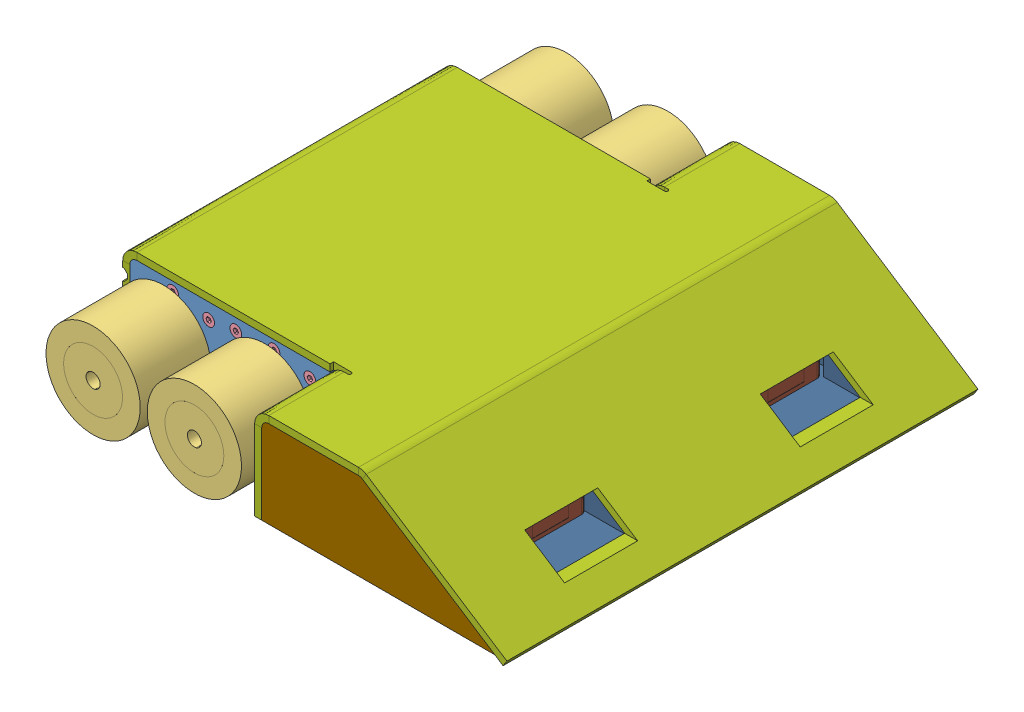
SolidWorks assembly Robot, configuration Predeterminado. Lengths in mm.
Overall size (195.19 45.36 282.25).
54 component instances, 11 part files, 14 mates.
Components (placement in the parent):
- Tren_Trasero-1: Tren_Trasero [Predeterminado] at (-15.877 7.2886 280.5) size (88.08 45.36 282.25)
  - Ruedas_D-1: Ruedas_D [Predeterminado] at (3.9847 -7.6146 27.875) size (88.08 41.65 151.25)
    - Bracket_Motor_D-1: Bracket_Motor_D [Predeterminado] at (-5.4362 4.6538 77.5) size (85 37 5)
    - Titan-37mm-500rpm-2: Titan-37mm-500rpm [Predeterminado] at (16.0638 4.6538 56) x (0.34202 -0.939693 0) z (0 0 1) size (37 37 78.75)
    - Titan-37mm-500rpm-3: Titan-37mm-500rpm [Predeterminado] at (-26.9341 4.6545 56) x (0.34202 -0.939693 0) z (0 0 1) size (37 37 78.75)
    - js4030-wheel-cad-1: js4030-wheel-cad [Predeterminado] at (-53.7606 2.8053 140) x (-1 0 0) z (0 0 -1) size (40 40 30)
    - js4030-wheel-cad-2: js4030-wheel-cad [Predeterminado] at (-10.7627 2.8046 140) x (-1 0 0) z (0 0 -1) size (40 40 30)
    - Tornillo M3x15-1: Tornillo M3x15 [Predeterminado] at (-42.2008 7.3453 67.5) size (5 5 15.24)
    - Tornillo M3x15-2: Tornillo M3x15 [Predeterminado] at (-32.2376 19.219 67.5) size (5 5 15.24)
    - Tornillo M3x15-4: Tornillo M3x15 [Predeterminado] at (-21.6349 -9.9115 67.5) size (5 5 15.24)
    - Tornillo M3x15-5: Tornillo M3x15 [Predeterminado] at (-36.8995 -7.2199 67.5) size (5 5 15.24)
    - Tornillo M3x15-6: Tornillo M3x15 [Predeterminado] at (-16.973 16.5274 67.5) size (5 5 15.24)
    - Tornillo M3x15-7: Tornillo M3x15 [Predeterminado] at (-11.6717 1.9622 67.5) size (5 5 15.24)
    - Tornillo M3x15-8: Tornillo M3x15 [Predeterminado] at (6.1005 -7.2199 67.5) size (5 5 15.24)
    - Tornillo M3x15-9: Tornillo M3x15 [Predeterminado] at (31.3283 1.9622 67.5) size (5 5 15.24)
    - Tornillo M3x15-10: Tornillo M3x15 [Predeterminado] at (21.3651 -9.9115 67.5) size (5 5 15.24)
    - Tornillo M3x15-11: Tornillo M3x15 [Predeterminado] at (0.7992 7.3453 67.5) size (5 5 15.24)
    - Tornillo M3x15-12: Tornillo M3x15 [Predeterminado] at (26.027 16.5274 67.5) size (5 5 15.24)
    - Tornillo M3x15-13: Tornillo M3x15 [Predeterminado] at (10.7624 19.219 67.5) size (5 5 15.24)
  - Ruedas_I-1: Ruedas_I [Predeterminado] at (17.4264 0.7496 -103.125) size (88.08 44.6 128.99)
    - Bracket_Motor_I-1: Bracket_Motor_I [Predeterminado] at (-18.8779 -3.7105 77.5) size (85 37 5)
    - Titan-37mm-500rpm-3: Titan-37mm-500rpm [Predeterminado] at (2.6242 -3.7097 104) x (-0.34202 0.939693 0) z (0 0 -1) size (37 37 78.75)
    - Titan-37mm-500rpm-4: Titan-37mm-500rpm [Predeterminado] at (-40.3758 -3.7097 104) x (-0.34202 0.939693 0) z (0 0 -1) size (37 37 78.75)
    - Tornillo M3x15-1: Tornillo M3x15 [Predeterminado] at (-45.6792 10.8547 92.5) x (-1 0 0) z (0 0 -1) size (5 5 15.24)
    - Tornillo M3x15-2: Tornillo M3x15 [Predeterminado] at (-30.4147 8.1632 92.5) x (-1 0 0) z (0 0 -1) size (5 5 15.24)
    - Tornillo M3x15-3: Tornillo M3x15 [Predeterminado] at (-25.1134 -6.402 92.5) x (-1 0 0) z (0 0 -1) size (5 5 15.24)
    - Tornillo M3x15-4: Tornillo M3x15 [Predeterminado] at (-35.0766 -18.2757 92.5) x (-1 0 0) z (0 0 -1) size (5 5 15.24)
    - Tornillo M3x15-5: Tornillo M3x15 [Predeterminado] at (-50.3411 -15.5842 92.5) x (-1 0 0) z (0 0 -1) size (5 5 15.24)
    - Tornillo M3x15-6: Tornillo M3x15 [Predeterminado] at (17.8866 -6.402 92.5) x (-1 0 0) z (0 0 -1) size (5 5 15.24)
    - Tornillo M3x15-7: Tornillo M3x15 [Predeterminado] at (-7.3411 -15.5842 92.5) x (-1 0 0) z (0 0 -1) size (5 5 15.24)
    - Tornillo M3x15-8: Tornillo M3x15 [Predeterminado] at (-12.6424 -1.0189 92.5) x (-1 0 0) z (0 0 -1) size (5 5 15.24)
    - Tornillo M3x15-9: Tornillo M3x15 [Predeterminado] at (-55.6424 -1.0189 92.5) x (-1 0 0) z (0 0 -1) size (5 5 15.24)
    - Tornillo M3x15-10: Tornillo M3x15 [Predeterminado] at (12.5853 8.1632 92.5) x (-1 0 0) z (0 0 -1) size (5 5 15.24)
    - Tornillo M3x15-11: Tornillo M3x15 [Predeterminado] at (7.9234 -18.2757 92.5) x (-1 0 0) z (0 0 -1) size (5 5 15.24)
    - Tornillo M3x15-12: Tornillo M3x15 [Predeterminado] at (-2.6792 10.8547 92.5) x (-1 0 0) z (0 0 -1) size (5 5 15.24)
    - js4030-wheel-cad-1: js4030-wheel-cad [Predeterminado] at (16.2907 -5.5589 20) size (40 40 30)
    - js4030-wheel-cad-2: js4030-wheel-cad [Predeterminado] at (-26.7093 -5.5589 20) size (40 40 30)
  - Struct_1-1: Struct_1 [Predeterminado] at (-1.4515 10.5391 -20.625) size (5 37 126)
  - Tornillo M3x15-5: Tornillo M3x15 [Predeterminado] at (-1.4515 -16.4609 95.375) size (5 5 15.24)
  - Tornillo M3x15-6: Tornillo M3x15 [Predeterminado] at (-1.4515 10.5391 95.375) size (5 5 15.24)
  - Tornillo M3x15-7: Tornillo M3x15 [Predeterminado] at (-1.4515 -16.4609 -10.625) x (-1 0 0) z (0 0 -1) size (5 5 15.24)
  - Tornillo M3x15-8: Tornillo M3x15 [Predeterminado] at (-1.4515 10.5391 -10.625) x (-1 0 0) z (0 0 -1) size (5 5 15.24)
- chapa-1: chapa [Predeterminado] at (-19.8285 22.8278 322.875) size (195.11 42.27 200)
- Bateria-1: Bateria [Predeterminado] at (51.1715 -10.1722 322.875) x (0 0 -1) z (1 0 0) size (136 27 45)
- Chapa_Lateral-1: Chapa_Lateral [Predeterminado] at (25.6549 -14.1615 222.875) size (98.98 37 5)
- Chapa_Lateral-2: Chapa_Lateral [Predeterminado] at (25.6715 -14.1722 417.875) size (98.98 37 5)
- Sensores_front-1: Sensores_front [Predeterminado] at (109.3283 -4.587 132.875) size (51.37 28.17 190)
  - soporte_sensores_front-1: soporte_sensores_front [Predeterminado] at (-28.062 -12.5853 95) size (43.38 28.17 190)
  - OMRON-E3Z-D62_D82-1: OMRON-E3Z-D62_D82 [Predeterminado] at (-14.062 2.3454 152.7) x (-1 0 0) z (0 -1 0) size (24.99 38.09 10.8)
  - OMRON-E3Z-D62_D82-2: OMRON-E3Z-D62_D82 [Predeterminado] at (-14.062 2.3454 227.3) x (-1 0 0) z (0 1 0) size (24.99 38.09 10.8)
  - Tornillo M3x15-1: Tornillo M3x15 [Predeterminado] at (-14.062 5.4147 127.3) x (1 0 0) z (0 -1 0) size (5 5 15.24)
  - Tornillo M3x15-2: Tornillo M3x15 [Predeterminado] at (-14.062 5.4147 152.7) x (1 0 0) z (0 -1 0) size (5 5 15.24)
  - Tornillo M3x15-3: Tornillo M3x15 [Predeterminado] at (-14.062 5.4147 227.3) x (1 0 0) z (0 -1 0) size (5 5 15.24)
  - Tornillo M3x15-4: Tornillo M3x15 [Predeterminado] at (-14.062 5.4147 252.7) x (1 0 0) z (0 -1 0) size (5 5 15.24)
Mates (geometry in assembly coordinates):
- Coincidente1: coincident aligned: circle of Tren_Trasero-1/Ruedas_D-1/Bracket_Motor_D-1; circle of chapa-1
- Coincidente2: coincident aligned: plane of Tren_Trasero-1/Ruedas_D-1/Bracket_Motor_D-1 through (-17.3285 4.3278 390.875) normal (0 0 1); plane of chapa-1 through (-62.3285 25.8278 390.875) normal (0 0 1)
- Ancho1: width anti-aligned: plane of Bateria-1 through (73.6715 16.8278 390.875) normal (0 0 1); plane of Bateria-1 through (73.6715 16.8278 254.875) normal (0 0 -1); plane of chapa-1 through (67.6715 25.8278 222.875) normal (0 0 -1); plane of chapa-1 through (22.6715 25.8278 422.875) normal (0 0 1)
- Distancia1: distance = 3 mm anti-aligned: plane of Bateria-1 through (28.6715 16.8278 390.875) normal (-1 0 0); plane of chapa-1 through (25.6715 22.8278 322.875) normal (1 0 0)
- Distancia2: distance = 4 mm aligned: plane of Bateria-1 through (51.1715 -10.1722 322.875) normal (0 -1 0); plane of chapa-1 through (22.6715 -14.1722 422.875) normal (0 -1 0)
- Coincidente3: coincident aligned: plane of Chapa_Lateral-1 through (124.6299 -14.1615 227.875) normal (0.544639 0.838671 0); plane of Chapa_Lateral-2 through (124.6465 -14.1722 422.875) normal (0.544639 0.838671 0)
- Coincidente4: coincident anti-aligned: plane of chapa-1 through (25.6715 22.8278 322.875) normal (1 0 0); plane of Chapa_Lateral-2 through (25.6715 -14.1722 422.875) normal (-1 0 0)
- Coincidente5: coincident aligned: plane of chapa-1 through (22.6715 25.8278 422.875) normal (0 0 1); plane of Chapa_Lateral-2 through (28.6715 19.8278 422.875) normal (0 0 1)
- Coincidente7: coincident anti-aligned: line of chapa-1 through (28.6715 22.8278 422.875) axis (1 0 0); line of Chapa_Lateral-2 through (66.7828 22.8278 422.875) axis (-1 0 0)
- Coincidente8: coincident aligned: plane of chapa-1 through (22.6715 -14.1722 222.875) normal (0 0 -1); plane of Chapa_Lateral-1 through (28.6549 19.8385 222.875) normal (0 0 -1)
- Coincidente9: coincident anti-aligned: plane of Chapa_Lateral-2 through (28.6715 19.8278 417.875) normal (0 0 -1); plane of Sensores_front-1/soporte_sensores_front-1 through (81.2663 -17.1722 417.875) normal (0 0 1)
- Ancho2: width anti-aligned: plane of Sensores_front-1/soporte_sensores_front-1 through (81.2663 -17.1722 417.875) normal (0 0 1); plane of Sensores_front-1/soporte_sensores_front-1 through (81.2663 -17.1722 227.875) normal (0 0 -1); plane of Tren_Trasero-1/Ruedas_I-1/Bracket_Motor_I-1 through (-17.3285 4.3278 254.875) normal (0 0 -1); plane of Tren_Trasero-1/Ruedas_D-1/Bracket_Motor_D-1 through (-17.3285 4.3278 390.875) normal (0 0 1)
- Coincidente12: coincident aligned: line of Chapa_Lateral-2 through (25.6715 -14.1722 417.875) axis (1 0 0); line of Sensores_front-1/soporte_sensores_front-1 through (81.2663 -14.1722 417.875) axis (1 0 0)
- Coincidente13: coincident: line of Chapa_Lateral-2 through (124.6465 -14.1722 422.875) axis (0 0 -1); point of Sensores_front-1/soporte_sensores_front-1
